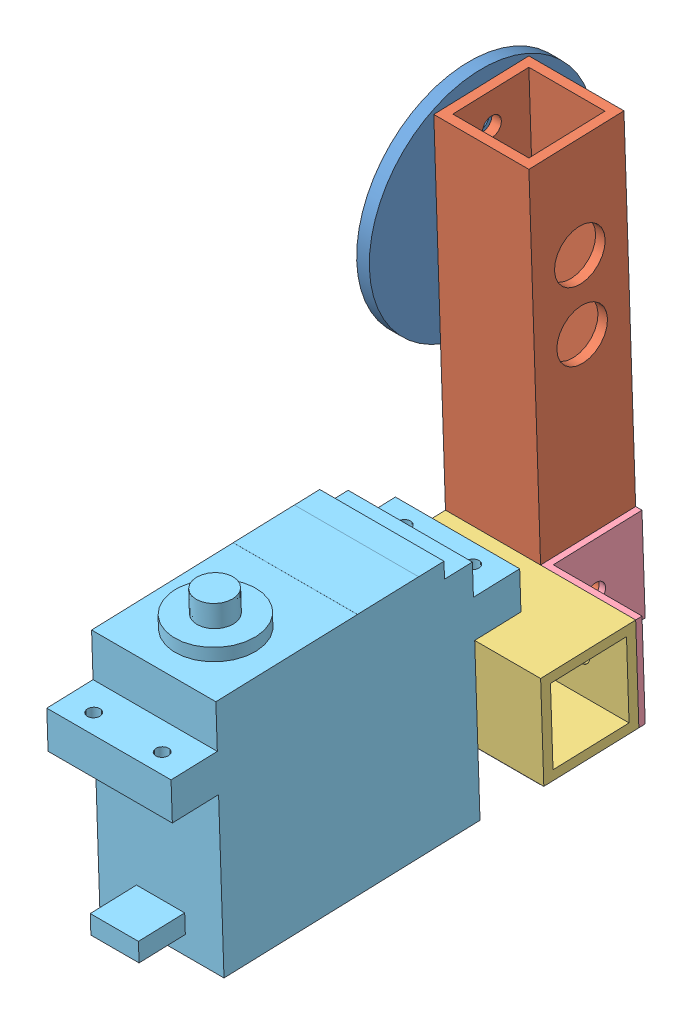
SolidWorks assembly Assem2, configuration ﾃﾞﾌｫﾙﾄ. Lengths in mm.
Overall size (35.1 88.1 87.87).
6 component instances, 5 part files, 9 mates.
Components (placement in the parent):
- 腕_刀_円盤-1: 腕_刀_円盤 [ﾃﾞﾌｫﾙﾄ] at (0.4693 20.3878 55) x (0 0.033485 -0.999439) z (1 0 0) size (35.6 35.6 5.1)
- 腕_刀_伸ばし-1: 腕_刀_伸ばし [ﾃﾞﾌｫﾙﾄ] at (9.8794 36.3867 55.3033) x (1 0 0) z (0 -0.999439 -0.033485) size (15 15 85)
- 腕_刀_サーボ固定-1: 腕_刀_サーボ固定 [ﾃﾞﾌｫﾙﾄ] at (32.8693 -26.8044 67.9371) x (0 -0.033485 0.999439) z (-1 0 0) size (15 15 30)
- 腕_刀_L字固定-1: 腕_刀_L字固定 [ﾃﾞﾌｫﾙﾄ] at (2.8693 -42.6577 65.8565) x (0 -0.033485 0.999439) z (1 0 0) size (15 15 15)
- 腕_刀_L字固定-2: 腕_刀_L字固定 [ﾃﾞﾌｫﾙﾄ] at (23.3307 -33.5435 52.0458) x (1 0 0) z (0 0.999439 0.033485) size (15 15 15)
- サーボ_MG995-2: サーボ_MG995 [ﾃﾞﾌｫﾙﾄ] at (38.3339 -44.9986 95.3099) x (-1 0 0) z (0 0.999439 0.033485) size (19.6 55 43.9)
Mates (geometry in assembly coordinates):
- 一致4: coincident anti-aligned: plane of 腕_刀_円盤-1 through (2.8693 20.3878 55) normal (1 0 0); plane of 腕_刀_伸ばし-1 through (2.8693 -48.8246 60.1853) normal (-1 0 0)
- 同心円2: concentric anti-aligned: circle of 腕_刀_円盤-1; circle of 腕_刀_伸ばし-1
- 同心円3: concentric anti-aligned: circle of 腕_刀_円盤-1; circle of 腕_刀_伸ばし-1
- 一致7: coincident anti-aligned: circle of 腕_刀_伸ばし-1; circle of 腕_刀_L字固定-2
- 一致8: coincident anti-aligned: circle of 腕_刀_サーボ固定-1; circle of 腕_刀_L字固定-2
- 一致9: coincident anti-aligned: circle of 腕_刀_伸ばし-1; cylinder of 腕_刀_L字固定-1 through (10.3693 -41.6637 70.4309) axis (0 0.033485 -0.999439) radius 1.5
- 一致10: coincident anti-aligned: circle of 腕_刀_サーボ固定-1; circle of 腕_刀_L字固定-1
- 一致11: coincident aligned: circle of 腕_刀_サーボ固定-1; circle of サーボ_MG995-2
- 一致12: coincident aligned: circle of 腕_刀_サーボ固定-1; circle of サーボ_MG995-2
